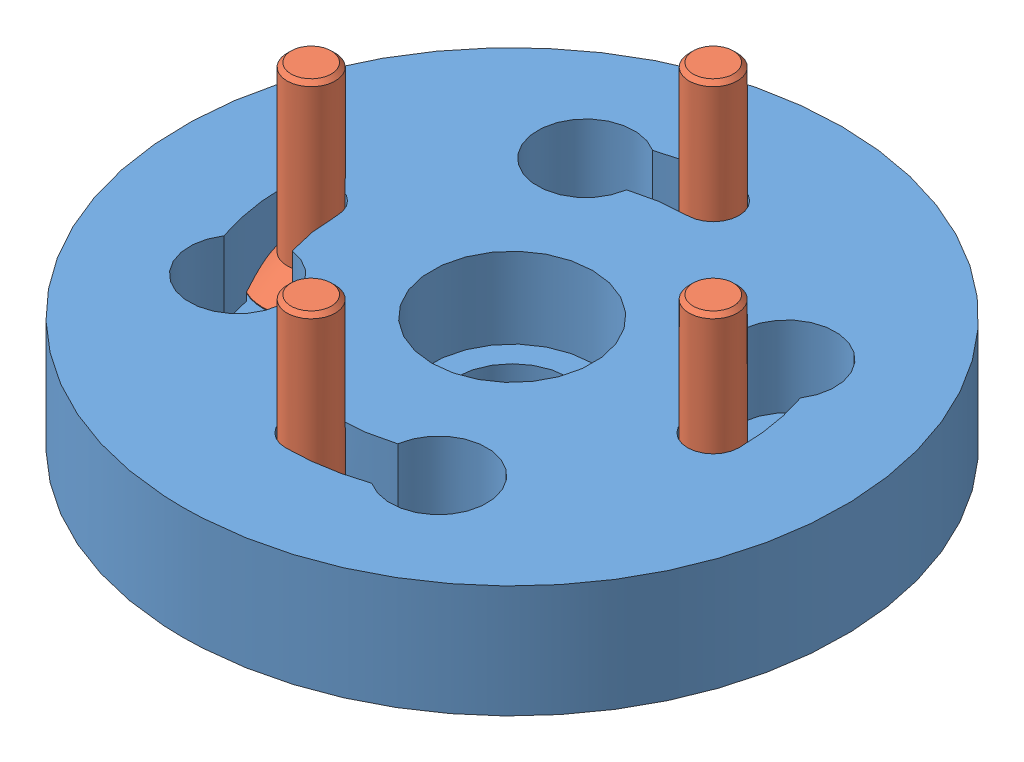
SolidWorks assembly mt-6, configuration Varsayılan. Lengths in mm.
Overall size (41 14.45 41).
5 component instances, 2 part files, 15 mates.
Components (placement in the parent):
- mt-6-1: mt-6 [Varsayılan] at origin size (41 7 41)
- m3x10-1: m3x10 [Varsayılan] at (0 2.7 -12.5) size (6 11.75 6)
- m3x10-2: m3x10 [Varsayılan] at (0 2.7 12.5) size (6 11.75 6)
- m3x10-4: m3x10 [Varsayılan] at (12.5 2.7 0) x (0 0 1) z (-1 0 0) size (6 11.75 6)
- m3x10-6: m3x10 [Varsayılan] at (-12.5 2.7 0) x (-1 0 0) z (0 0 -1) size (6 11.75 6)
Mates (geometry in assembly coordinates):
- Coincident1: coincident anti-aligned: plane of mt-6-1 through (-6.25 2 -10.8253) normal (0 1 0); plane of m3x10-1 through (0 2.7 -12.5) normal (0 -1 0)
- Distance1: distance = 12.5 mm: cylinder of m3x10-1 through (0 14.45 -12.5) axis (0 -1 0) radius 1.5; cylinder of mt-6-1 through (0 2 0) axis (0 1 0) radius 5
- Coincident2: coincident aligned: plane of mt-6-1 through (0 0 0) normal (1 0 0); plane of m3x10-1 through (0 2.7 -12.5) normal (1 0 0)
- Coincident3: coincident anti-aligned: plane of mt-6-1 through (-6.25 2 -10.8253) normal (0 1 0); plane of m3x10-2 through (0 2.7 12.5) normal (0 -1 0)
- Distance6: distance = 12.5 mm: cylinder of m3x10-2 through (0 14.45 12.5) axis (0 -1 0) radius 1.5; cylinder of mt-6-1 through (0 2 0) axis (0 1 0) radius 5
- Coincident10: coincident aligned: plane of mt-6-1 through (0 0 0) normal (1 0 0); plane of m3x10-2 through (0 2.7 12.5) normal (1 0 0)
- Coincident11: coincident anti-aligned: plane of mt-6-1 through (-6.25 2 -10.8253) normal (0 1 0); plane of m3x10-4 through (12.5 2.7 0) normal (0 -1 0)
- Distance8: distance = 12.5 mm: cylinder of m3x10-4 through (12.5 14.45 0) axis (0 -1 0) radius 1.5; cylinder of mt-6-1 through (0 2 0) axis (0 1 0) radius 5
- Coincident12: coincident aligned: plane of mt-6-1 through (0 0 0) normal (0 0 1); plane of m3x10-4 through (12.5 2.7 0) normal (0 0 1)
- Coincident14: coincident anti-aligned: plane of mt-6-1 through (-10.8253 2 6.25) normal (0 1 0); plane of m3x10-6 through (-12.5 2.7 0) normal (0 -1 0)
- Coincident15: coincident: plane of m3x10-6 through (-12.5 2.7 0) normal (0 0 -1); plane of mt-6-1 through (0 0 0) normal (0 0 1)
- Coincident17: coincident aligned: cone of mt-6-1 through (0 2.75 -12.5) axis (0 1 0); cone of m3x10-1 through (0 4.45 -12.5) axis (0 1 0)
- Coincident18: coincident aligned: cone of mt-6-1 through (0 2.75 12.5) axis (0 1 0); cone of m3x10-2 through (0 4.45 12.5) axis (0 1 0)
- Coincident19: coincident aligned: cone of mt-6-1 through (12.5 2.75 0) axis (0 1 0); cone of m3x10-4 through (12.5 4.45 0) axis (0 1 0)
- Coincident20: coincident aligned: cone of mt-6-1 through (-12.5 2.75 0) axis (0 1 0); cone of m3x10-6 through (-12.5 4.45 0) axis (0 1 0)
